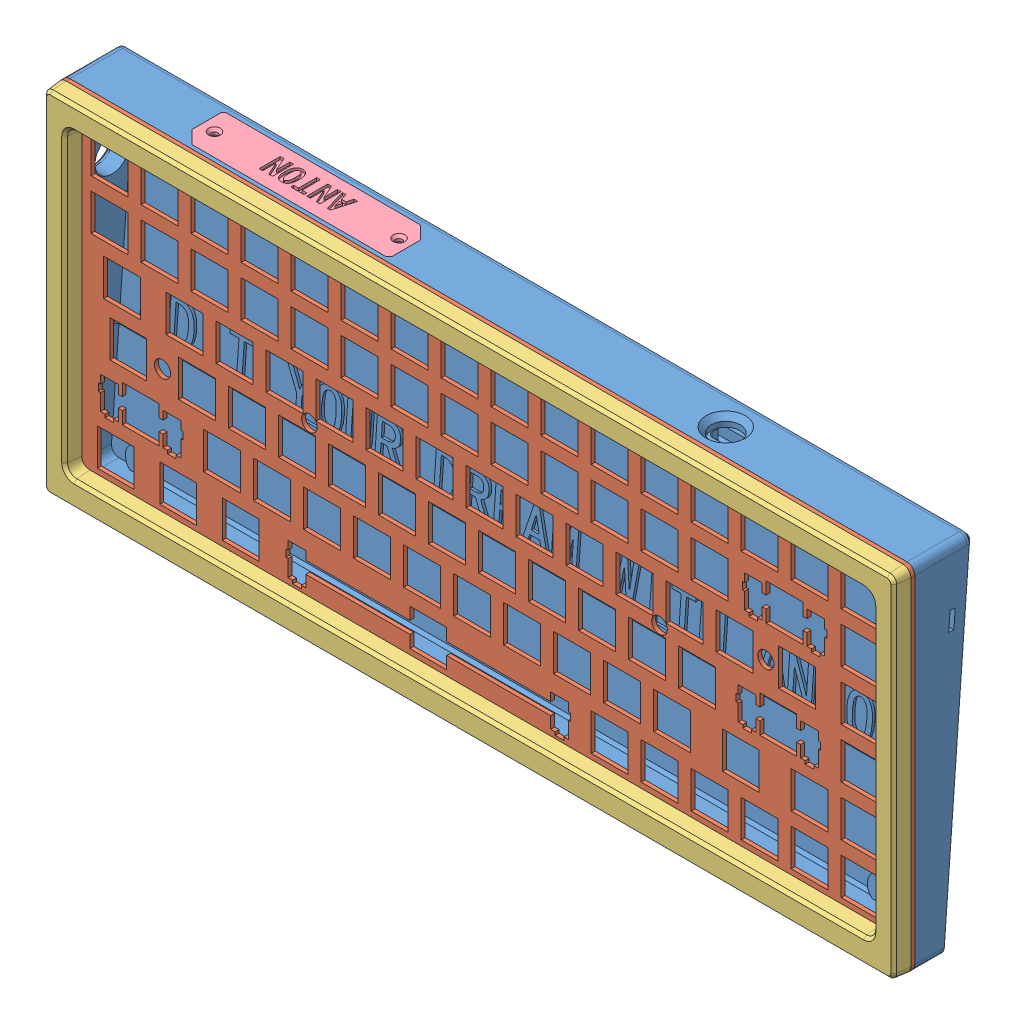
SolidWorks assembly assembly, configuration 默认. Lengths in mm.
Overall size (325.37 134.39 30.34).
4 component instances, 4 part files, 4 mates.
Components (placement in the parent):
- downV2-1: downV2 [默认] at (-149.6458 -57.8371 336.7913) size (325.37 134.39 22.84)
- plate-2: plate [默认] at (-149.6458 -57.8371 336.7913) size (324.8 134.3 1.5)
- up-1: up [默认] at (155.3444 -59.8371 338.2913) x (-1 0 0) z (0 0 -1) size (324.8 134.3 6)
- logo-2: logo [默认] at (-102.0964 64.7209 316.4068) x (-1 0 0) z (0 1 0) size (80.31 17.07 2)
Mates (geometry in assembly coordinates):
- 重合2: coincident aligned: line of downV2-1 through (-159.5507 63.7209 336.7913) axis (0 -1 0); line of plate-2 through (-159.5507 63.7209 336.7913) axis (0 -1 0)
- 重合3: coincident aligned: line of downV2-1 through (162.2502 66.7209 336.7913) axis (-1 0 0); line of plate-2 through (162.2502 66.7209 336.7913) axis (-1 0 0)
- 重合6: coincident aligned: line of downV2-1 through (-111.5507 64.7209 335.2913) axis (1 0 0); line of logo-2 through (-111.5507 64.7209 335.2913) axis (1 0 0)
- 重合7: coincident aligned: line of downV2-1 through (-116.5507 64.7209 319.2932) axis (0 0 1); line of logo-2 through (-116.5507 64.7209 319.2245) axis (0 0 1)
